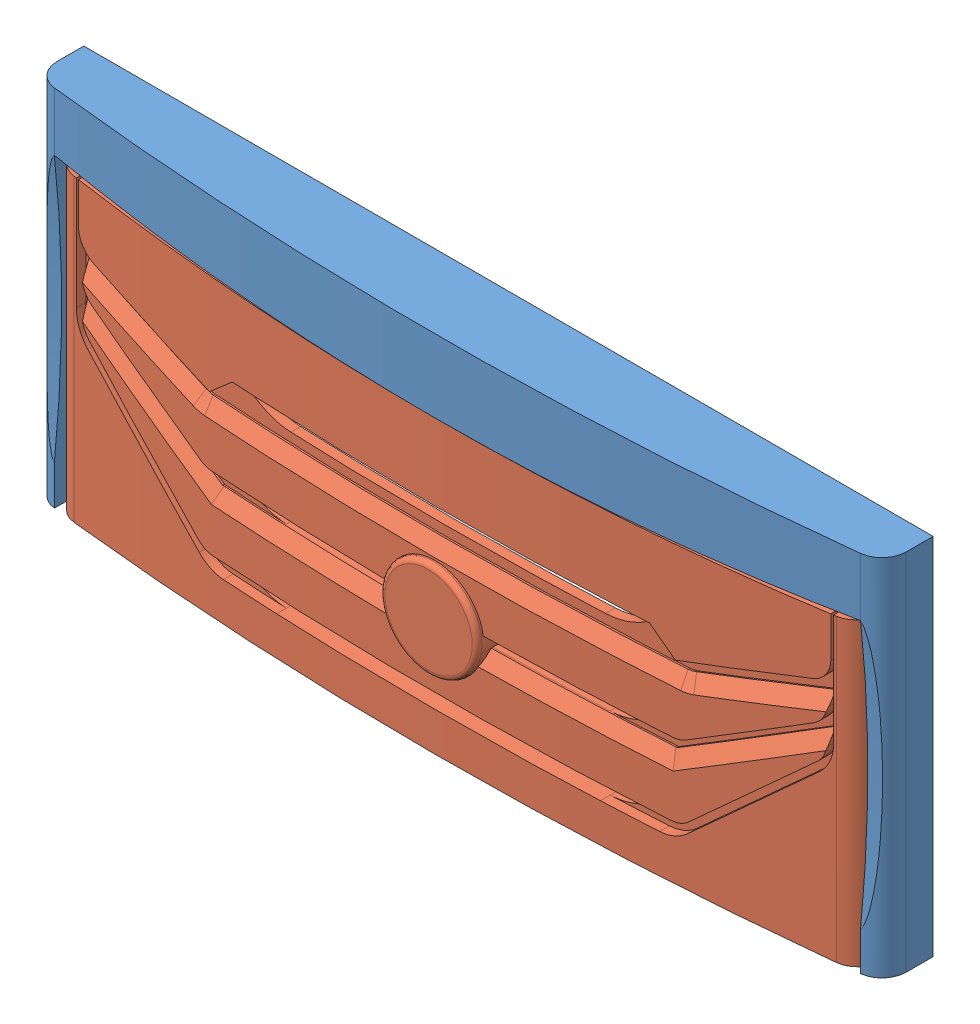
SolidWorks assembly ashok leyland coel assembly, configuration Default. Lengths in mm.
Overall size (175 85.12 34.17).
2 component instances, 2 part files, 3 mates.
Components (placement in the parent):
- ashok leyland front cowl-1: ashok leyland front cowl [Default] at (49.5529 51.3527 169.8053) size (175 85.12 34.17)
- ashok leyland front cowl2-1: ashok leyland front cowl2 [Default] at (49.5814 51.3527 169.8053) size (166 80.25 28)
Mates (geometry in assembly coordinates):
- Parallel3: parallel: plane of ashok leyland front cowl-1 through (132.6152 114.3527 157.3053) normal (-1 0 0); plane of ashok leyland front cowl2-1 through (132.5814 51.3527 157.3053) normal (1 0 0)
- Coincident4: coincident: plane of ashok leyland front cowl-1 through (-37.9471 126.3527 157.3053) normal (0 0 -1); plane of ashok leyland front cowl2-1 through (-37.9186 113.3527 157.3053) normal (0 0 -1)
- Coincident5: coincident aligned: plane of ashok leyland front cowl-1 through (49.5529 51.3527 -566.0539) normal (0 -1 0); plane of ashok leyland front cowl2-1 through (49.5814 51.3527 -566.0539) normal (0 -1 0)
